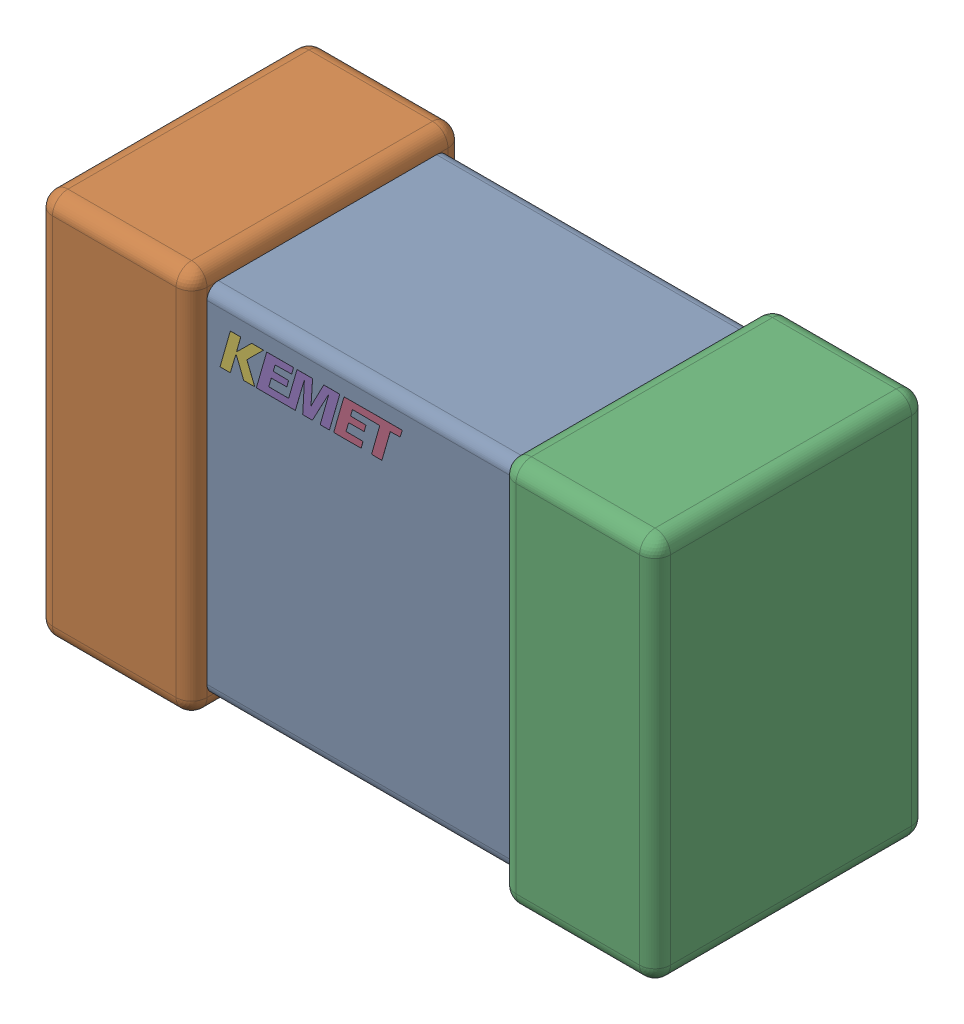
SolidWorks assembly C12.step, configuration Default. Lengths in mm.
Overall size (2 1.25 0.88).
3 component instances, 3 part files, 0 mates.
Components (placement in the parent):
- Cap_KEMET_C0805C472J3HAC_eec.step-1: Cap_KEMET_C0805C472J3HAC_eec.step [Default] at (57.277 14.097 0) size (1 1.15 0.78)
- Cap_KEMET_C0805C472J3HAC_eec-7.step-1: Cap_KEMET_C0805C472J3HAC_eec-7.step [Default] at (57.277 14.097 0) size (2 1.25 0.88)
- Cap_KEMET_C0805C472J3HAC_eec-8.step-1: Cap_KEMET_C0805C472J3HAC_eec-8.step [Default] at (57.277 14.097 0) size (0.59 0.12 0)
